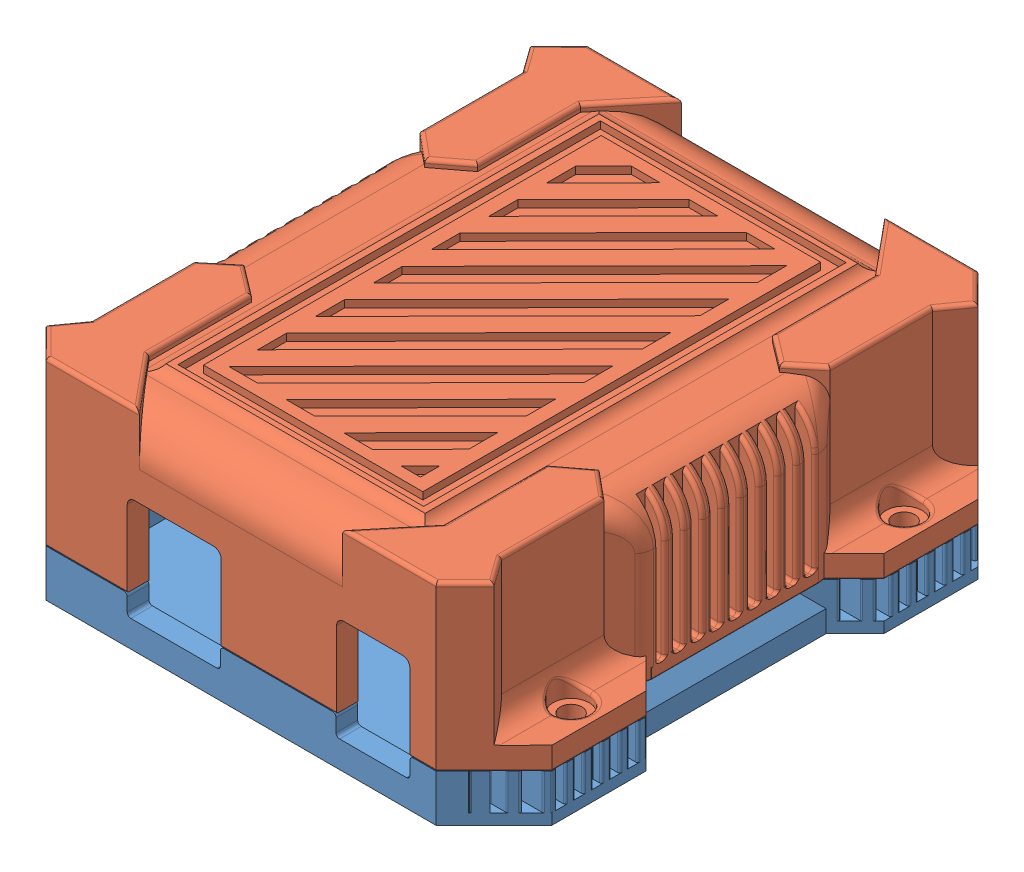
SolidWorks assembly Assem3, configuration Default. Lengths in mm.
Overall size (70 29.1 77).
2 component instances, 2 part files, 2 mates.
Components (placement in the parent):
- reciever case bottom.stp-1: reciever case bottom.stp [Default] at origin size (70 6.5 75)
- reciever case top.stp-1: reciever case top.stp [Default] at (-6.4475 3.6 0) size (70 22.6 77)
Mates (geometry in assembly coordinates):
- Coincident1: coincident: plane of reciever case bottom.stp-1 through (0 5 22.9891) normal (0 1 0); plane of reciever case top.stp-1 through (25.8674 5 0.8564) normal (0 -1 0)
- Concentric1: concentric anti-aligned: circle of reciever case bottom.stp-1; circle of reciever case top.stp-1
